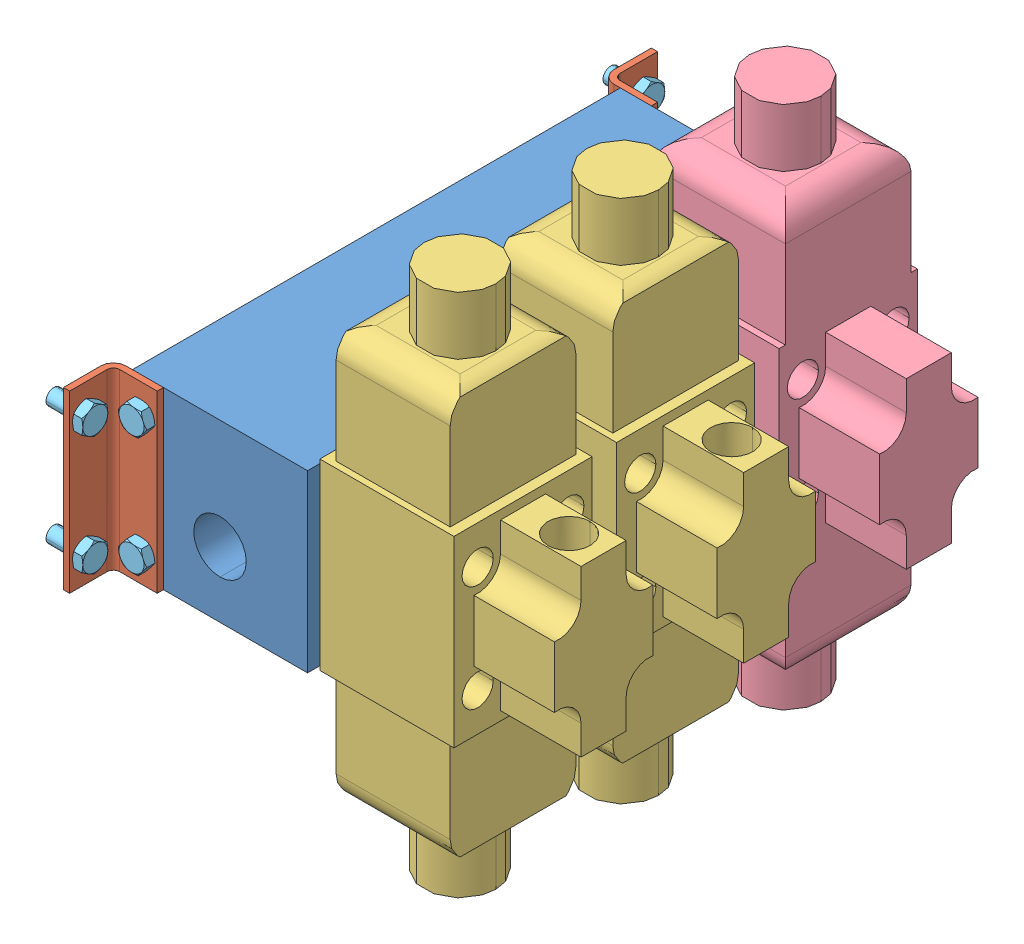
SolidWorks assembly 01-119-00-0, configuration Default. Lengths in mm.
Overall size (220.24 266.21 298.46).
14 component instances, 5 part files, 32 mates.
Components (placement in the parent):
- DAMAN-AD05S033S VALVE BLOCK-1: DAMAN-AD05S033S VALVE BLOCK [Default] at origin size (88.92 88.92 247.67)
- DAMANAD05S033S MOUNTING BRACKET-1: DAMANAD05S033S MOUNTING BRACKET [Default] at (0 88.9 -247.65) x (1 0 0) z (0 0 -1) size (25.42 88.91 25.42)
- HYVAIR-D05S-2C-12D-35 SOLENOID-1: HYVAIR-D05S-2C-12D-35 SOLENOID [Default] at origin size (108.98 266.21 70.11)
- DAMANAD05S033S MOUNTING BRACKET-2: DAMANAD05S033S MOUNTING BRACKET [Default] at origin size (25.42 88.91 25.42)
- HYVAIR-D05S-2H-12D-35 SOLENOID-1: HYVAIR-D05S-2H-12D-35 SOLENOID [Default] at (0 0 -165.0746) size (108.98 266.21 70.11)
- .313-18 X-8: .313-18 X [Default] at (-22.352 14.224 17.526) x (0 0 1) z (-1 0 0) size (12.71 14.68 21.05)
- .313-18 X-9: .313-18 X [Default] at (-22.352 74.676 17.526) x (0 0 1) z (-1 0 0) size (12.71 14.68 21.05)
- .313-18 X-10: .313-18 X [Default] at (-22.352 14.224 -265.176) x (0 0 1) z (-1 0 0) size (12.71 14.68 21.05)
- .313-18 X-11: .313-18 X [Default] at (-22.352 74.676 -265.176) x (0 0 1) z (-1 0 0) size (12.71 14.68 21.05)
- .313-18 X-12: .313-18 X [Default] at (7.874 74.676 -234.95) x (-0.923728 -0.383049 0) z (0 0 1) size (12.71 14.68 21.05)
- .313-18 X-13: .313-18 X [Default] at (7.874 14.224 -234.95) x (-0.923728 -0.383049 0) z (0 0 1) size (12.71 14.68 21.05)
- .313-18 X-14: .313-18 X [Default] at (7.874 74.676 -12.7) x (0.923728 0.383049 0) z (0 0 -1) size (12.71 14.68 21.05)
- .313-18 X-15: .313-18 X [Default] at (7.874 14.224 -12.7) x (0.923728 0.383049 0) z (0 0 -1) size (12.71 14.68 21.05)
- HYVAIR-D05S-2C-12D-35 SOLENOID-2: HYVAIR-D05S-2C-12D-35 SOLENOID [Default] at (0 0 -82.5373) size (108.98 266.21 70.11)
Mates (geometry in assembly coordinates):
- Coincident159934: coincident anti-aligned: plane of DAMAN-AD05S033S VALVE BLOCK-1 through (0 0 -247.65) normal (0 0 -1); plane of DAMANAD05S033S MOUNTING BRACKET-1 through (15.748 88.9 -247.65) normal (0 0 1)
- Concentric39018: concentric anti-aligned: cylinder of DAMAN-AD05S033S VALVE BLOCK-1 through (7.874 14.224 -247.65) axis (0 0 1) radius 3.2004; cylinder of DAMANAD05S033S MOUNTING BRACKET-1 through (7.874 14.224 -247.65) axis (0 0 -1) radius 4.3656
- Concentric39019: concentric anti-aligned: cylinder of DAMAN-AD05S033S VALVE BLOCK-1 through (7.874 74.676 -247.65) axis (0 0 1) radius 3.2004; cylinder of DAMANAD05S033S MOUNTING BRACKET-1 through (7.874 74.676 -247.65) axis (0 0 -1) radius 4.3656
- Coincident159935: coincident anti-aligned: plane of DAMAN-AD05S033S VALVE BLOCK-1 through (0 0 0) normal (0 0 1); plane of DAMANAD05S033S MOUNTING BRACKET-2 through (15.748 0 0) normal (0 0 -1)
- Concentric39020: concentric anti-aligned: cylinder of DAMAN-AD05S033S VALVE BLOCK-1 through (7.874 14.224 0) axis (0 0 -1) radius 3.2004; cylinder of DAMANAD05S033S MOUNTING BRACKET-2 through (7.874 14.224 0) axis (0 0 1) radius 4.3656
- Concentric39021: concentric anti-aligned: cylinder of DAMAN-AD05S033S VALVE BLOCK-1 through (7.874 74.676 0) axis (0 0 -1) radius 3.2004; cylinder of DAMANAD05S033S MOUNTING BRACKET-2 through (7.874 74.676 0) axis (0 0 1) radius 4.3656
- Concentric39022: concentric aligned: cylinder of HYVAIR-D05S-2C-12D-35 SOLENOID-1 through (114.808 17.4752 -18.2626) axis (-1 0 0) radius 3.429; cylinder of DAMAN-AD05S033S VALVE BLOCK-1 through (88.9 17.4752 -18.2626) axis (-1 0 0) radius 2.4892
- Concentric39023: concentric aligned: cylinder of DAMAN-AD05S033S VALVE BLOCK-1 through (88.9 17.4752 -64.3128) axis (-1 0 0) radius 2.4892; cylinder of HYVAIR-D05S-2C-12D-35 SOLENOID-1 through (114.808 17.4752 -64.3128) axis (-1 0 0) radius 3.429
- Coincident159936: coincident anti-aligned: plane of DAMAN-AD05S033S VALVE BLOCK-1 through (88.9 88.9 -247.65) normal (1 0 0); plane of HYVAIR-D05S-2C-12D-35 SOLENOID-1 through (88.9 90.932 -76.3397) normal (-1 0 0)
- Coincident159937: coincident anti-aligned: plane of DAMAN-AD05S033S VALVE BLOCK-1 through (88.9 88.9 -247.65) normal (1 0 0); plane of HYVAIR-D05S-2H-12D-35 SOLENOID-1 through (88.9 135.382 -241.4143) normal (-1 0 0)
- Concentric39024: concentric anti-aligned: cylinder of DAMANAD05S033S MOUNTING BRACKET-2 through (-6.477 14.224 17.526) axis (-1 0 0) radius 4.3656; cylinder of .313-18 X-8 through (-22.352 14.224 17.526) axis (1 0 0) radius 3.9878
- Coincident159938: coincident anti-aligned: plane of DAMANAD05S033S MOUNTING BRACKET-2 through (-6.477 88.9 6.35) normal (1 0 0); plane of .313-18 X-8 through (-6.477 7.7426 23.876) normal (-1 0 0)
- Concentric39025: concentric anti-aligned: cylinder of DAMANAD05S033S MOUNTING BRACKET-2 through (-6.477 74.676 17.526) axis (-1 0 0) radius 4.3656; cylinder of .313-18 X-9 through (-22.352 74.676 17.526) axis (1 0 0) radius 3.9878
- Coincident159939: coincident anti-aligned: plane of DAMANAD05S033S MOUNTING BRACKET-2 through (-6.477 88.9 6.35) normal (1 0 0); plane of .313-18 X-9 through (-6.477 68.1946 23.876) normal (-1 0 0)
- Concentric39026: concentric anti-aligned: cylinder of DAMANAD05S033S MOUNTING BRACKET-1 through (-6.477 14.224 -265.176) axis (-1 0 0) radius 4.3656; cylinder of .313-18 X-10 through (-22.352 14.224 -265.176) axis (1 0 0) radius 3.9878
- Coincident159941: coincident anti-aligned: plane of DAMANAD05S033S MOUNTING BRACKET-1 through (-6.477 0 -254) normal (1 0 0); plane of .313-18 X-10 through (-6.477 7.7426 -258.826) normal (-1 0 0)
- Concentric39027: concentric anti-aligned: cylinder of DAMANAD05S033S MOUNTING BRACKET-1 through (-6.477 74.676 -265.176) axis (-1 0 0) radius 4.3656; cylinder of .313-18 X-11 through (-22.352 74.676 -265.176) axis (1 0 0) radius 3.9878
- Coincident159942: coincident anti-aligned: plane of DAMANAD05S033S MOUNTING BRACKET-1 through (-6.477 0 -254) normal (1 0 0); plane of .313-18 X-11 through (-6.477 68.1946 -258.826) normal (-1 0 0)
- Concentric39028: concentric aligned: cylinder of DAMANAD05S033S MOUNTING BRACKET-1 through (7.874 74.676 -247.65) axis (0 0 -1) radius 4.3656; cylinder of .313-18 X-12 through (7.874 74.676 -234.95) axis (0 0 -1) radius 3.9878
- Coincident159943: coincident anti-aligned: plane of DAMANAD05S033S MOUNTING BRACKET-1 through (-3.302 88.9 -250.825) normal (0 0 -1); plane of .313-18 X-12 through (-0.4743 78.2306 -250.825) normal (0 0 1)
- Concentric39029: concentric aligned: cylinder of DAMANAD05S033S MOUNTING BRACKET-1 through (7.874 14.224 -247.65) axis (0 0 -1) radius 4.3656; cylinder of .313-18 X-13 through (7.874 14.224 -234.95) axis (0 0 -1) radius 3.9878
- Coincident159944: coincident anti-aligned: plane of DAMANAD05S033S MOUNTING BRACKET-1 through (-3.302 88.9 -250.825) normal (0 0 -1); plane of .313-18 X-13 through (-0.4743 17.7786 -250.825) normal (0 0 1)
- Concentric39030: concentric aligned: cylinder of DAMANAD05S033S MOUNTING BRACKET-2 through (7.874 74.676 0) axis (0 0 1) radius 4.3656; cylinder of .313-18 X-14 through (7.874 74.676 -12.7) axis (0 0 1) radius 3.9878
- Coincident159945: coincident anti-aligned: plane of DAMANAD05S033S MOUNTING BRACKET-2 through (-3.302 0 3.175) normal (0 0 1); plane of .313-18 X-14 through (11.257 83.0954 3.175) normal (0 0 -1)
- Concentric39031: concentric aligned: cylinder of DAMANAD05S033S MOUNTING BRACKET-2 through (7.874 14.224 0) axis (0 0 1) radius 4.3656; cylinder of .313-18 X-15 through (7.874 14.224 -12.7) axis (0 0 1) radius 3.9878
- Coincident159946: coincident anti-aligned: plane of DAMANAD05S033S MOUNTING BRACKET-2 through (-3.302 0 3.175) normal (0 0 1); plane of .313-18 X-15 through (11.257 22.6434 3.175) normal (0 0 -1)
- Coincident159947: coincident: point of ?
- Concentric39032: concentric aligned: cylinder of DAMAN-AD05S033S VALVE BLOCK-1 through (88.9 17.4752 -183.3372) axis (-1 0 0) radius 2.4892; cylinder of HYVAIR-D05S-2H-12D-35 SOLENOID-1 through (114.808 17.4752 -183.3372) axis (-1 0 0) radius 3.429
- Concentric39033: concentric aligned: cylinder of DAMAN-AD05S033S VALVE BLOCK-1 through (88.9 17.4752 -229.3874) axis (-1 0 0) radius 2.4892; cylinder of HYVAIR-D05S-2H-12D-35 SOLENOID-1 through (114.808 17.4752 -229.3874) axis (-1 0 0) radius 3.429
- Concentric39034: concentric aligned: cylinder of DAMAN-AD05S033S VALVE BLOCK-1 through (88.9 17.4752 -100.7999) axis (-1 0 0) radius 2.4892; cylinder of HYVAIR-D05S-2C-12D-35 SOLENOID-2 through (114.808 17.4752 -100.7999) axis (-1 0 0) radius 3.429
- Concentric39035: concentric aligned: cylinder of DAMAN-AD05S033S VALVE BLOCK-1 through (88.9 17.4752 -146.8501) axis (-1 0 0) radius 2.4892; cylinder of HYVAIR-D05S-2C-12D-35 SOLENOID-2 through (114.808 17.4752 -146.8501) axis (-1 0 0) radius 3.429
- Coincident159948: coincident anti-aligned: plane of DAMAN-AD05S033S VALVE BLOCK-1 through (88.9 88.9 -247.65) normal (1 0 0); plane of HYVAIR-D05S-2C-12D-35 SOLENOID-2 through (88.9 90.932 -158.877) normal (-1 0 0)
